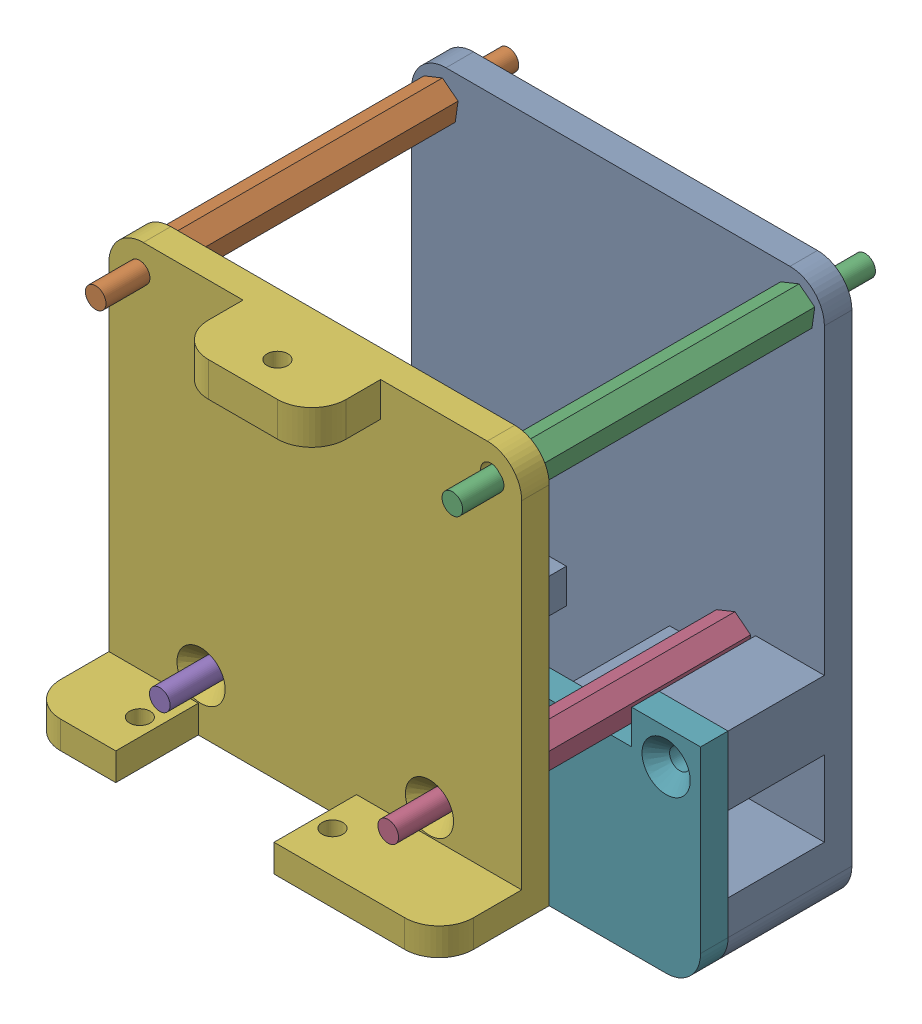
SolidWorks assembly Assemblage1, configuration Défaut. Lengths in mm.
Overall size (60 80 66).
7 component instances, 4 part files, 10 mates.
Components (placement in the parent):
- base roulante pami-1: base roulante pami [Défaut] at (-45.4597 44.078 -9) size (60 80 18)
- entretoise 4cm-1: entretoise 4cm [Défaut] at (-41.3833 39.6754 35) x (-0.923728 -0.383049 0) z (0 0 -1) size (5.77 5.03 60)
- entretoise 4cm-2: entretoise 4cm [Défaut] at (10.4638 39.6754 35) x (-0.923728 -0.383049 0) z (0 0 -1) size (5.77 5.03 60)
- entretoise 4cm-3: entretoise 4cm [Défaut] at (1.1433 -6.2532 35) x (-0.923728 -0.383049 0) z (0 0 -1) size (5.77 5.03 60)
- entretoise 4cm-4: entretoise 4cm [Défaut] at (-32.0627 -6.2532 -5) size (5.77 5.03 60)
- hat base roullante-1: hat base roullante [Défaut] at (-45.4597 -13.922 39) x (1 0 0) z (0 0 -1) size (60 58 16)
- capot rue-1: capot rue [Défaut] at (14.5403 -4.922 13) x (-1 0 0) z (0 0 -1) size (60 31 4)
Mates (geometry in assembly coordinates):
- Coïncidente11: coincident anti-aligned: plane of entretoise 4cm-2 through (10.4638 39.6754 35) normal (0 0 1); plane of hat base roullante-1 through (9.5403 39.078 35) normal (0 0 -1)
- Coïncidente12: coincident anti-aligned: circle of base roulante pami-1; circle of entretoise 4cm-1
- Coïncidente13: coincident anti-aligned: circle of base roulante pami-1; circle of entretoise 4cm-2
- Coïncidente14: coincident anti-aligned: circle of base roulante pami-1; circle of entretoise 4cm-3
- Coïncidente15: coincident anti-aligned: circle of base roulante pami-1; circle of entretoise 4cm-4
- Parallèle3: parallel aligned: plane of base roulante pami-1 through (-40.4597 44.078 -5) normal (0 1 0); plane of hat base roullante-1 through (-40.4597 44.078 35) normal (0 1 0)
- Coaxiale2: concentric anti-aligned: circle of base roulante pami-1; circle of capot rue-1
- Coïncidente18: coincident anti-aligned: plane of base roulante pami-1 through (-45.4597 44.078 9) normal (0 0 1); plane of capot rue-1 through (14.5403 -4.922 9) normal (0 0 -1)
- Coaxiale3: concentric anti-aligned: circle of base roulante pami-1; circle of capot rue-1
- Coïncidente19: coincident anti-aligned: circle of entretoise 4cm-4; circle of hat base roullante-1
